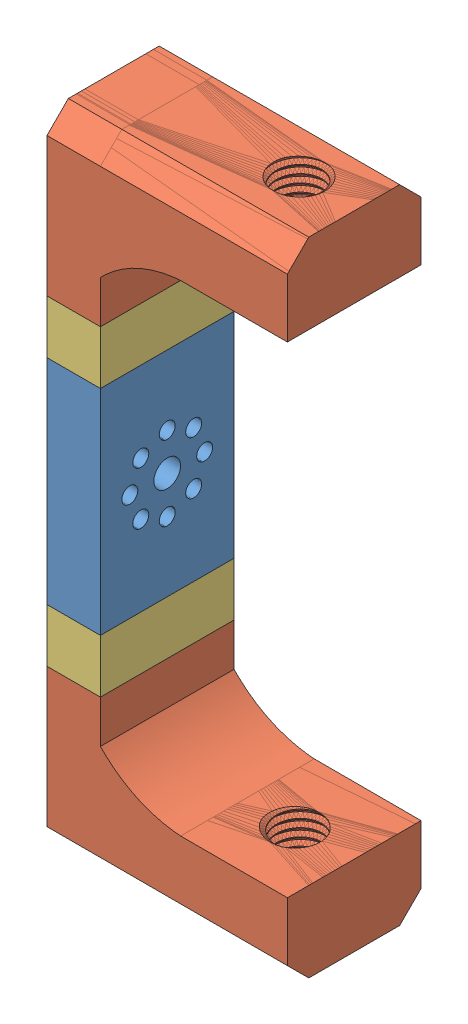
SolidWorks assembly redesigned, configuration 默认. Lengths in mm.
Overall size (44.98 120.03 25).
5 component instances, 3 part files, 12 mates.
Components (placement in the parent):
- mid-1: mid [默认] at (21.6028 4.3675 40) size (10 40 25)
- small-1: small [默认] at (21.6028 -5.6325 40) size (44.98 30.02 25)
- con-1: con [默认] at (5.9045 -25.6325 41.1218) x (0 0 -1) z (0 1 0) size (25 10 10)
- con-2: con [默认] at (5.9045 34.3675 38.8782) x (0 0 1) z (0 -1 0) size (25 10 10)
- small-2: small [默认] at (21.6028 14.3675 40) x (1 0 0) z (0 0 -1) size (44.98 30.02 25)
Mates (geometry in assembly coordinates):
- 重合3: coincident anti-aligned: plane of mid-1 through (-8.2268 -15.6325 27.5) normal (0 -1 0); plane of con-1 through (5.9045 -15.6325 41.1218) normal (0 1 0)
- 重合4: coincident aligned: plane of mid-1 through (21.6028 4.3675 52.5) normal (0 0 1); plane of con-1 through (-2.8585 -15.6325 52.5) normal (0 0 1)
- 重合5: coincident aligned: plane of mid-1 through (-2.8585 4.3675 40) normal (-1 0 0); plane of con-1 through (-2.8585 -15.6325 52.5) normal (-1 0 0)
- 重合6: coincident anti-aligned: plane of mid-1 through (-8.2268 24.3675 27.5) normal (0 1 0); plane of con-2 through (5.9045 24.3675 38.8782) normal (0 -1 0)
- 重合9: coincident aligned: plane of mid-1 through (21.6028 4.3675 52.5) normal (0 0 1); plane of con-2 through (-2.8585 24.3675 52.5) normal (0 0 1)
- 重合10: coincident aligned: plane of mid-1 through (-2.8585 4.3675 40) normal (-1 0 0); plane of con-2 through (-2.8585 24.3675 27.5) normal (-1 0 0)
- 重合11: coincident anti-aligned: plane of small-1 through (-5.4142 -25.6325 27.5) normal (0 1 0); plane of con-1 through (5.9045 -25.6325 41.1218) normal (0 -1 0)
- 重合12: coincident aligned: plane of small-1 through (21.6028 -5.6325 52.5) normal (0 0 1); plane of con-1 through (-2.8585 -15.6325 52.5) normal (0 0 1)
- 重合13: coincident aligned: plane of small-1 through (-2.8585 -5.6325 40) normal (-1 0 0); plane of con-1 through (-2.8585 -15.6325 52.5) normal (-1 0 0)
- 重合14: coincident aligned: plane of con-2 through (-2.8585 24.3675 27.5) normal (-1 0 0); plane of small-2 through (-2.8585 14.3675 40) normal (-1 0 0)
- 重合15: coincident aligned: plane of con-2 through (-2.8585 24.3675 52.5) normal (0 0 1); plane of small-2 through (21.6028 14.3675 52.5) normal (0 0 1)
- 重合16: coincident anti-aligned: plane of con-2 through (5.9045 34.3675 38.8782) normal (0 1 0); plane of small-2 through (-5.4142 34.3675 52.5) normal (0 -1 0)
